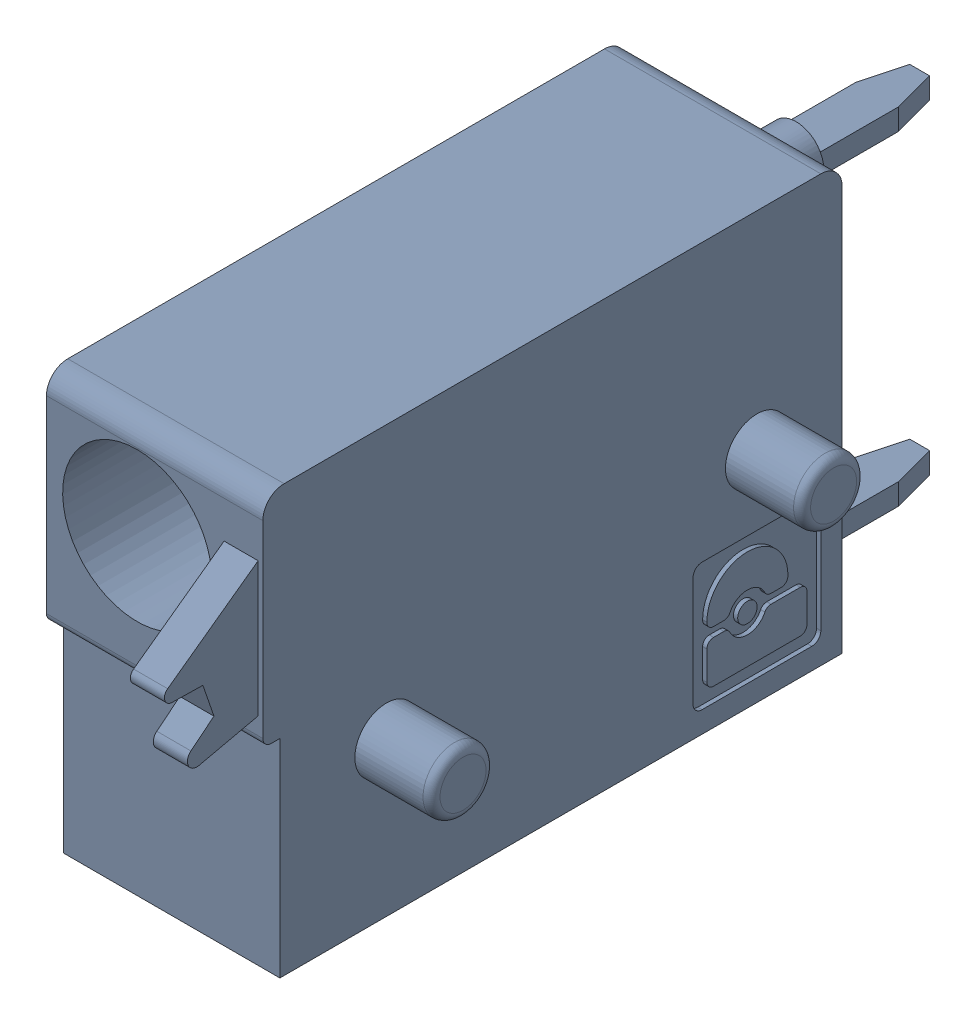
SolidWorks assembly J15, configuration Default. Lengths in mm.
Overall size (6.88 10 19.2).
2 component instances, 1 part files, 0 mates.
Components (placement in the parent):
- 1790348-1: 1790348 [Default] at (29.8451 -7.6199 0) x (0 1 0) z (1 0 0) size (10 19.2 6.88)
  - ffkds-v2-5.08-1: ffkds-v2-5.08 [Default] at (-23.7414 -38.158 -2.54) x (0 -1 0) z (0 0 1) size (19.2 10 6.88)
